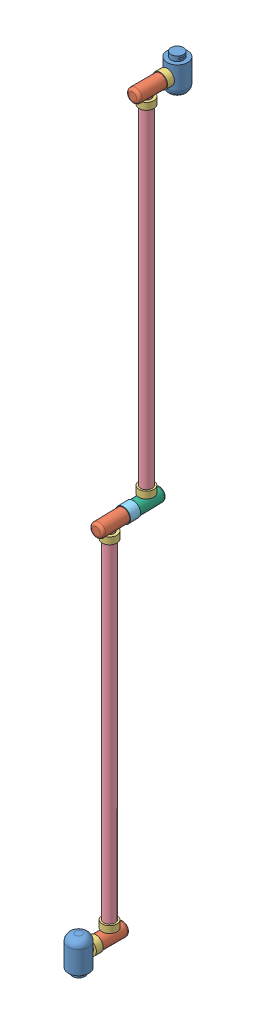
SolidWorks assembly Assem1, configuration Default. Lengths in mm.
Overall size (313.36 10888.86 1749.84).
15 component instances, 6 part files, 32 mates.
Components (placement in the parent):
- Part1-3: Part1 [Default] at (568.6656 -337.3937 213.7494) size (300 500 300)
- Part2-4: Part2 [Default] at (568.6656 -87.9634 213.7494) x (-1 0 0) z (0 -1 0) size (195 650 195)
- MotorJoint-7: MotorJoint [Default] at (568.6656 -87.9634 63.7494) x (0.998719 -0.050604 0) z (0.050604 0.998719 0) size (215 100 215)
- Part3-3: Part3 [Default] at (568.6656 -87.9634 -236.2506) x (-0.498239 0 -0.86704) z (0.86704 0 -0.498239) size (165 5195 165)
- MotorJoint-8: MotorJoint [Default] at (568.6656 9.5366 -236.2506) x (-0.945856 0 -0.324588) z (0.324588 0 -0.945856) size (215 100 215)
- MotorJoint-9: MotorJoint [Default] at (568.6656 4909.5366 -236.2506) x (-0.432543 0 0.901613) z (-0.901613 0 -0.432543) size (215 100 215)
- Part2-5: Part2 [Default] at (557.7384 5107.0366 -686.1179) x (-0.999705 0 0.024283) z (0 1 0) size (195 650 195)
- MotorJoint2-2: MotorJoint2 [Default] at (563.8091 5107.0366 -436.1917) x (-0.446568 0.894684 0.010847) z (-0.89442 -0.4467 0.021725) size (215 150 215)
- Part4-2: Part4 [Default] at (566.2373 5107.0366 -336.2211) x (-0.999705 0 0.024283) z (0 -1 0) size (195 400 195)
- Part3-4: Part3 [Default] at (555.3101 10302.0366 -786.0885) x (0.836333 0 0.548222) z (0.548222 0 -0.836333) size (165 5195 165)
- MotorJoint-10: MotorJoint [Default] at (555.3101 5204.5366 -786.0885) x (-0.999964 0 -0.008497) z (0.008497 0 -0.999964) size (215 100 215)
- MotorJoint-11: MotorJoint [Default] at (555.3101 10204.5366 -786.0885) x (0.836529 0 0.547923) z (0.547923 0 -0.836529) size (215 100 215)
- MotorJoint-12: MotorJoint [Default] at (555.3101 10302.0366 -1086.0885) x (0.184476 0.982837 0) z (0.982837 -0.184476 0) size (215 100 215)
- Part1-4: Part1 [Default] at (555.3101 10551.4669 -1236.0885) x (1 0 0) z (0 0 -1) size (300 500 300)
- Part2-6: Part2 [Default] at (555.3101 10302.0366 -1236.0885) x (-1 0 0) z (0 1 0) size (195 650 195)
Mates (geometry in assembly coordinates):
- Coincident2: coincident anti-aligned: plane of Part2-4 through (568.6656 -87.9634 -36.2506) normal (0 0 1); plane of MotorJoint-7 through (568.6656 -87.9634 -36.2506) normal (0 0 -1)
- Concentric2: concentric anti-aligned: cylinder of Part2-4 through (568.6656 -87.9634 -36.2506) axis (0 0 1) radius 67.5; cylinder of MotorJoint-7 through (568.6656 -87.9634 63.7494) axis (0 0 -1) radius 67.5
- Concentric3: concentric aligned: cylinder of Part1-3 through (568.6656 -87.9634 63.7494) axis (0 0 1) radius 67.5; cylinder of Part2-4 through (568.6656 -87.9634 -36.2506) axis (0 0 1) radius 67.5
- Coincident3: coincident anti-aligned: plane of Part1-3 through (568.6656 -87.9634 213.7494) normal (0 0 -1); plane of Part2-4 through (568.6656 -87.9634 213.7494) normal (0 0 1)
- Concentric4: concentric anti-aligned: cylinder of Part3-3 through (568.6656 109.5366 -236.2506) axis (0 -1 0) radius 67.5; cylinder of MotorJoint-8 through (568.6656 9.5366 -236.2506) axis (0 1 0) radius 67.5
- Coincident4: coincident anti-aligned: plane of Part3-3 through (568.6656 109.5366 -236.2506) normal (0 -1 0); plane of MotorJoint-8 through (568.6656 109.5366 -236.2506) normal (0 1 0)
- Concentric5: concentric aligned: cylinder of Part2-4 through (568.6656 9.5366 -236.2506) axis (0 -1 0) radius 67.5; cylinder of Part3-3 through (568.6656 109.5366 -236.2506) axis (0 -1 0) radius 67.5
- Coincident5: coincident anti-aligned: plane of Part2-4 through (568.6656 -87.9634 -236.2506) normal (0 1 0); plane of Part3-3 through (568.6656 -87.9634 -236.2506) normal (0 -1 0)
- Concentric7: concentric aligned: cylinder of Part3-3 through (568.6656 4909.5366 -236.2506) axis (0 1 0) radius 67.5; cylinder of MotorJoint-9 through (568.6656 4909.5366 -236.2506) axis (0 1 0) radius 67.5
- Coincident6: coincident anti-aligned: plane of Part3-3 through (568.6656 4909.5366 -236.2506) normal (0 1 0); plane of MotorJoint-9 through (568.6656 4909.5366 -236.2506) normal (0 -1 0)
- Concentric8: concentric aligned: cylinder of Part3-3 through (568.6656 4909.5366 -236.2506) axis (0 1 0) radius 67.5; cylinder of Part2-5 through (568.6656 5009.5366 -236.2506) axis (0 1 0) radius 67.5
- Coincident7: coincident anti-aligned: plane of Part3-3 through (568.6656 5107.0366 -236.2506) normal (0 1 0); plane of Part2-5 through (568.6656 5107.0366 -236.2506) normal (0 -1 0)
- Concentric9: concentric aligned: cylinder of Part2-5 through (563.8091 5107.0366 -436.1917) axis (-0.024283 0 -0.999705) radius 67.5; cylinder of MotorJoint2-2 through (563.8091 5107.0366 -436.1917) axis (-0.024283 0 -0.999705) radius 67.5
- Coincident8: coincident anti-aligned: plane of Part2-5 through (563.8091 5107.0366 -436.1917) normal (-0.024283 0 -0.999705); plane of MotorJoint2-2 through (563.8091 5107.0366 -436.1917) normal (0.024283 0 0.999705)
- Concentric10: concentric anti-aligned: cylinder of Part2-5 through (563.8091 5107.0366 -436.1917) axis (-0.024283 0 -0.999705) radius 67.5; cylinder of Part4-2 through (557.7384 5107.0366 -686.1179) axis (0.024283 0 0.999705) radius 67.5
- Coincident9: coincident anti-aligned: plane of Part2-5 through (557.7384 5107.0366 -686.1179) normal (-0.024283 0 -0.999705); plane of Part4-2 through (557.7384 5107.0366 -686.1179) normal (0.024283 0 0.999705)
- Coincident10: coincident anti-aligned: plane of Part4-2 through (555.3101 5107.0366 -786.0885) normal (0 1 0); plane of Part3-4 through (555.3101 5107.0366 -786.0885) normal (0 -1 0)
- Concentric11: concentric aligned: cylinder of Part4-2 through (555.3101 5204.5366 -786.0885) axis (0 -1 0) radius 67.5; cylinder of Part3-4 through (555.3101 5304.5366 -786.0885) axis (0 -1 0) radius 67.5
- Coincident11: coincident anti-aligned: plane of Part3-4 through (555.3101 5304.5366 -786.0885) normal (0 -1 0); plane of MotorJoint-10 through (555.3101 5304.5366 -786.0885) normal (0 1 0)
- Concentric12: concentric anti-aligned: cylinder of Part3-4 through (555.3101 5304.5366 -786.0885) axis (0 -1 0) radius 67.5; cylinder of MotorJoint-10 through (555.3101 5204.5366 -786.0885) axis (0 1 0) radius 67.5
- Coincident12: coincident anti-aligned: plane of Part3-4 through (555.3101 10104.5366 -786.0885) normal (0 1 0); plane of MotorJoint-11 through (555.3101 10104.5366 -786.0885) normal (0 -1 0)
- Concentric13: concentric anti-aligned: cylinder of Part3-4 through (555.3101 10104.5366 -786.0885) axis (0 1 0) radius 67.5; cylinder of MotorJoint-11 through (555.3101 10204.5366 -786.0885) axis (0 -1 0) radius 67.5
- Coincident13: coincident anti-aligned: plane of Part3-4 through (555.3101 10302.0366 -786.0885) normal (0 1 0); plane of Part2-6 through (555.3101 10302.0366 -786.0885) normal (0 -1 0)
- Concentric14: concentric aligned: cylinder of Part3-4 through (555.3101 10104.5366 -786.0885) axis (0 1 0) radius 67.5; cylinder of Part2-6 through (555.3101 10204.5366 -786.0885) axis (0 1 0) radius 67.5
- Coincident14: coincident anti-aligned: plane of MotorJoint-12 through (555.3101 10302.0366 -986.0885) normal (0 0 1); plane of Part2-6 through (555.3101 10302.0366 -986.0885) normal (0 0 -1)
- Concentric15: concentric anti-aligned: cylinder of MotorJoint-12 through (555.3101 10302.0366 -1086.0885) axis (0 0 1) radius 67.5; cylinder of Part2-6 through (555.3101 10302.0366 -986.0885) axis (0 0 -1) radius 67.5
- Coincident15: coincident anti-aligned: plane of Part1-4 through (555.3101 10302.0366 -1236.0885) normal (0 0 1); plane of Part2-6 through (555.3101 10302.0366 -1236.0885) normal (0 0 -1)
- Concentric16: concentric aligned: cylinder of Part1-4 through (555.3101 10302.0366 -1086.0885) axis (0 0 -1) radius 67.5; cylinder of Part2-6 through (555.3101 10302.0366 -986.0885) axis (0 0 -1) radius 67.5
- Parallel1: parallel aligned: cylinder of Part1-3 through (568.6656 162.6063 213.7494) axis (0 -1 0) radius 150; cylinder of Part3-3 through (568.6656 5107.0366 -236.2506) axis (0 -1 0) radius 82.5
- Parallel2: parallel anti-aligned: cylinder of Part3-3 through (568.6656 5107.0366 -236.2506) axis (0 -1 0) radius 82.5; cylinder of Part3-4 through (555.3101 5107.0366 -786.0885) axis (0 1 0) radius 82.5
- Parallel3: parallel anti-aligned: cylinder of Part2-4 through (568.6656 -87.9634 -436.2506) axis (0 0 1) radius 97.5; cylinder of Part2-6 through (555.3101 10302.0366 -586.0885) axis (0 0 -1) radius 97.5
- Parallel4: parallel anti-aligned: cylinder of Part1-3 through (568.6656 162.6063 213.7494) axis (0 -1 0) radius 150; cylinder of Part1-4 through (555.3101 10051.4669 -1236.0885) axis (0 1 0) radius 150
